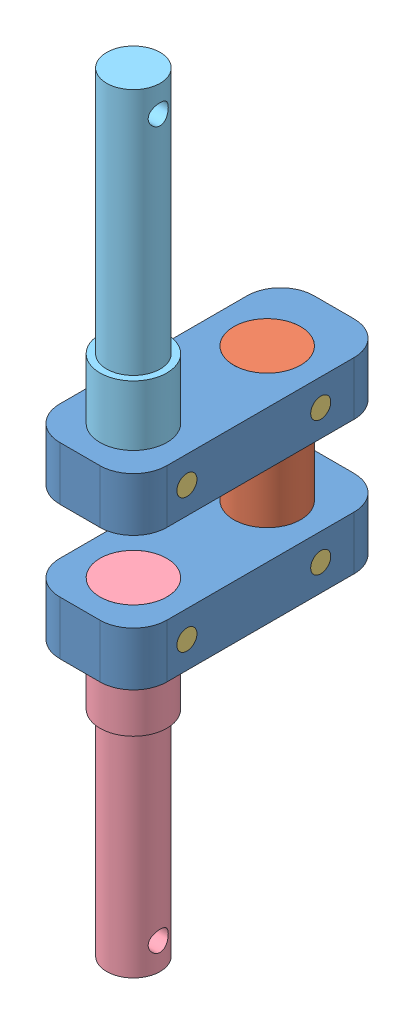
SolidWorks assembly Assem2, configuration Default. Lengths in mm.
Overall size (16 115 38).
9 component instances, 5 part files, 16 mates.
Components (placement in the parent):
- Part14-1: Part14 [Default] at (13.9631 16.7882 12.0828) size (16 8 38)
- Part15-1: Part15 [Default] at (14.2895 -3.2118 19.4621) x (0 0 1) z (-1 0 0) size (10 28 10)
- Part16-1: Part16 [Default] at (6.2895 20.7882 19.4621) x (0 0.06317 -0.998003) z (0 -0.998003 -0.06317) size (3 16 3)
- Part17-1: Part17 [Default] at (14.2895 4.7882 39.4621) x (0 0 -1) z (-1 0 0) size (10 49 10)
- Part18-1: Part18 [Default] at (14.2895 16.7882 39.4621) x (0 0 -1) z (1 0 0) size (10 54 10)
- Part14-2: Part14 [Default] at (13.9631 -3.2118 12.0828) size (16 8 38)
- Part16-2: Part16 [Default] at (6.2895 0.7882 19.4621) x (0 0.06317 -0.998003) z (0 -0.998003 -0.06317) size (3 16 3)
- Part16-5: Part16 [Default] at (6.2895 0.7882 39.4621) x (0 0.06317 -0.998003) z (0 -0.998003 -0.06317) size (3 16 3)
- Part16-6: Part16 [Default] at (6.2895 20.7882 39.4621) x (0 0.06317 -0.998003) z (0 -0.998003 -0.06317) size (3 16 3)
Mates (geometry in assembly coordinates):
- Concentric1: concentric aligned: cylinder of Part14-1 through (14.2895 24.7882 19.4621) axis (0 -1 0) radius 5; cylinder of Part15-1 through (14.2895 24.7882 19.4621) axis (0 -1 0) radius 4.9995
- Concentric2: concentric anti-aligned: cylinder of Part14-1 through (6.2895 20.7882 19.4621) axis (1 0 0) radius 1.5; cylinder of Part15-1 through (19.289 20.7882 19.4621) axis (-1 0 0) radius 1.5
- Concentric3: concentric anti-aligned: cylinder of Part14-1 through (6.2895 20.7882 19.4621) axis (1 0 0) radius 1.5; cylinder of Part16-1 through (22.2895 20.7882 19.4621) axis (-1 0 0) radius 1.5
- Coincident1: coincident aligned: plane of Part14-1 through (22.2895 24.7882 42.4621) normal (1 0 0); plane of Part16-1 through (22.2895 20.7882 19.4621) normal (1 0 0)
- Concentric11: concentric aligned: cylinder of Part15-1 through (14.2895 24.7882 19.4621) axis (0 -1 0) radius 4.9995; cylinder of Part14-2 through (14.2895 4.7882 19.4621) axis (0 -1 0) radius 5
- Concentric12: concentric anti-aligned: cylinder of Part15-1 through (19.289 0.7882 19.4621) axis (-1 0 0) radius 1.5; cylinder of Part14-2 through (6.2895 0.7882 19.4621) axis (1 0 0) radius 1.5
- Concentric13: concentric anti-aligned: cylinder of Part14-2 through (6.2895 0.7882 19.4621) axis (1 0 0) radius 1.5; cylinder of Part16-2 through (22.2895 0.7882 19.4621) axis (-1 0 0) radius 1.5
- Coincident5: coincident aligned: plane of Part14-2 through (22.2895 4.7882 42.4621) normal (1 0 0); plane of Part16-2 through (22.2895 0.7882 19.4621) normal (1 0 0)
- Concentric15: concentric aligned: cylinder of Part14-1 through (14.2895 24.7882 39.4621) axis (0 -1 0) radius 5; cylinder of Part18-1 through (14.2895 33.7882 39.4621) axis (0 -1 0) radius 5
- Concentric16: concentric aligned: cylinder of Part14-1 through (6.2895 20.7882 39.4621) axis (1 0 0) radius 1.5; cylinder of Part18-1 through (9.2895 20.7882 39.4621) axis (1 0 0) radius 1.5
- Concentric17: concentric anti-aligned: cylinder of Part17-1 through (14.2895 -12.2118 39.4621) axis (0 1 0) radius 5; cylinder of Part14-2 through (14.2895 4.7882 39.4621) axis (0 -1 0) radius 5
- Concentric18: concentric anti-aligned: cylinder of Part17-1 through (19.2895 0.7882 39.4621) axis (-1 0 0) radius 1.5; cylinder of Part14-2 through (6.2895 0.7882 39.4621) axis (1 0 0) radius 1.5
- Concentric19: concentric anti-aligned: cylinder of Part14-2 through (6.2895 0.7882 39.4621) axis (1 0 0) radius 1.5; cylinder of Part16-5 through (22.2895 0.7882 39.4621) axis (-1 0 0) radius 1.5
- Coincident7: coincident aligned: plane of Part14-2 through (6.2895 4.7882 42.4621) normal (-1 0 0); plane of Part16-5 through (6.2895 0.7882 39.4621) normal (-1 0 0)
- Concentric20: concentric anti-aligned: cylinder of Part14-1 through (6.2895 20.7882 39.4621) axis (1 0 0) radius 1.5; cylinder of Part16-6 through (22.2895 20.7882 39.4621) axis (-1 0 0) radius 1.5
- Coincident8: coincident aligned: plane of Part14-1 through (6.2895 24.7882 42.4621) normal (-1 0 0); plane of Part16-6 through (6.2895 20.7882 39.4621) normal (-1 0 0)
